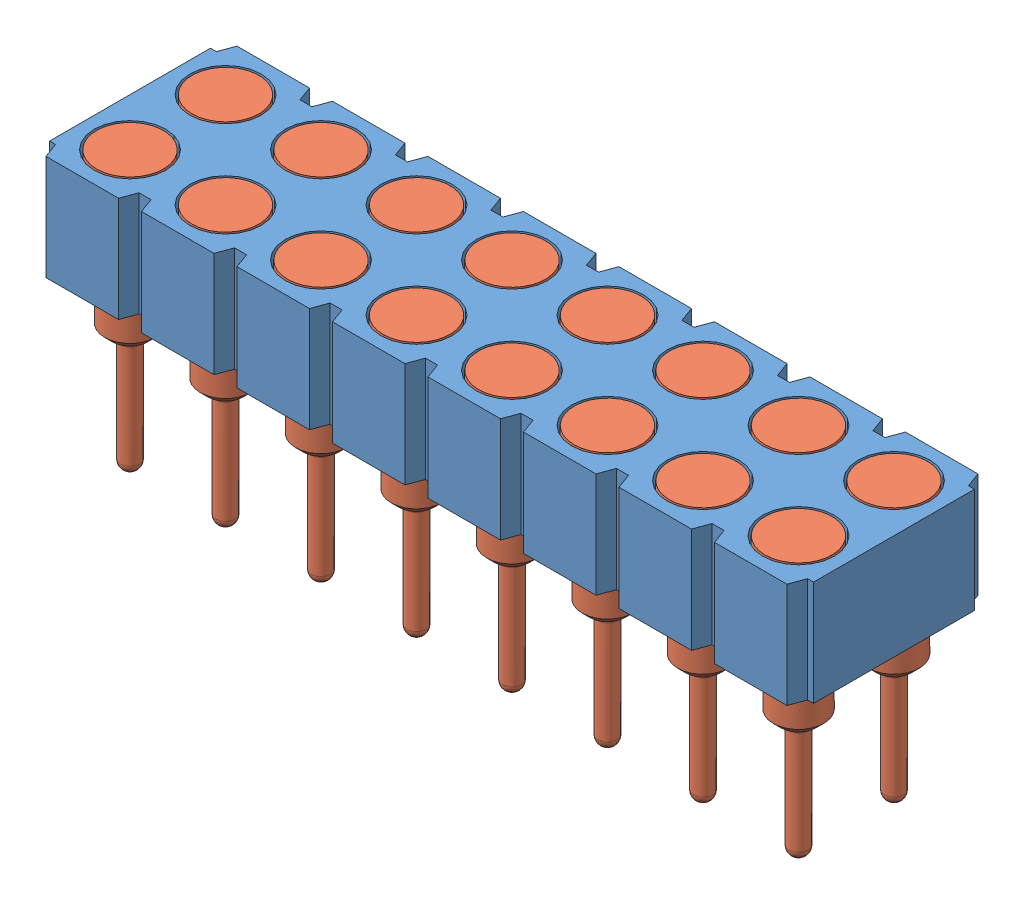
SolidWorks assembly mill-max-419-10-216-00-001000, configuration MillMaxsldprt2014419-XX-XXX-00-0010001610uGoldoverNickelPage14off. Lengths in mm.
Overall size (20.32 7.37 5.08).
17 component instances, 2 part files, 4 mates.
Components (placement in the parent):
- mill-max-419-10-216-00-001000_P4XX-21-010-00-000000-1: mill-max-419-10-216-00-001000_P4XX-21-010-00-000000 [P416-21-010-00-000000] at origin size (20.32 2.79 5.08)
- mill-max-419-10-216-00-001000_1942-1: mill-max-419-10-216-00-001000_1942 [Default] at (0.9644 0 -1.27) x (0 -1 0) z (0 0 1) size (7.37 1.78 1.78)
- mill-max-419-10-216-00-001000_1942-35: mill-max-419-10-216-00-001000_1942 [Default] at (0.9644 0 -3.81) x (0 -1 0) z (0 0 1) size (7.37 1.78 1.78)
- mill-max-419-10-216-00-001000_1942-36: mill-max-419-10-216-00-001000_1942 [Default] at (3.5044 0 -3.81) x (0 -1 0) z (0 0 1) size (7.37 1.78 1.78)
- mill-max-419-10-216-00-001000_1942-20: mill-max-419-10-216-00-001000_1942 [Default] at (3.5044 0 -1.27) x (0 -1 0) z (0 0 1) size (7.37 1.78 1.78)
- mill-max-419-10-216-00-001000_1942-37: mill-max-419-10-216-00-001000_1942 [Default] at (6.0444 0 -3.81) x (0 -1 0) z (0 0 1) size (7.37 1.78 1.78)
- mill-max-419-10-216-00-001000_1942-38: mill-max-419-10-216-00-001000_1942 [Default] at (8.5844 0 -3.81) x (0 -1 0) z (0 0 1) size (7.37 1.78 1.78)
- mill-max-419-10-216-00-001000_1942-39: mill-max-419-10-216-00-001000_1942 [Default] at (11.1244 0 -3.81) x (0 -1 0) z (0 0 1) size (7.37 1.78 1.78)
- mill-max-419-10-216-00-001000_1942-40: mill-max-419-10-216-00-001000_1942 [Default] at (13.6644 0 -3.81) x (0 -1 0) z (0 0 1) size (7.37 1.78 1.78)
- mill-max-419-10-216-00-001000_1942-41: mill-max-419-10-216-00-001000_1942 [Default] at (16.2044 0 -3.81) x (0 -1 0) z (0 0 1) size (7.37 1.78 1.78)
- mill-max-419-10-216-00-001000_1942-42: mill-max-419-10-216-00-001000_1942 [Default] at (18.7444 0 -3.81) x (0 -1 0) z (0 0 1) size (7.37 1.78 1.78)
- mill-max-419-10-216-00-001000_1942-29: mill-max-419-10-216-00-001000_1942 [Default] at (6.0444 0 -1.27) x (0 -1 0) z (0 0 1) size (7.37 1.78 1.78)
- mill-max-419-10-216-00-001000_1942-30: mill-max-419-10-216-00-001000_1942 [Default] at (8.5844 0 -1.27) x (0 -1 0) z (0 0 1) size (7.37 1.78 1.78)
- mill-max-419-10-216-00-001000_1942-31: mill-max-419-10-216-00-001000_1942 [Default] at (11.1244 0 -1.27) x (0 -1 0) z (0 0 1) size (7.37 1.78 1.78)
- mill-max-419-10-216-00-001000_1942-32: mill-max-419-10-216-00-001000_1942 [Default] at (13.6644 0 -1.27) x (0 -1 0) z (0 0 1) size (7.37 1.78 1.78)
- mill-max-419-10-216-00-001000_1942-33: mill-max-419-10-216-00-001000_1942 [Default] at (16.2044 0 -1.27) x (0 -1 0) z (0 0 1) size (7.37 1.78 1.78)
- mill-max-419-10-216-00-001000_1942-34: mill-max-419-10-216-00-001000_1942 [Default] at (18.7444 0 -1.27) x (0 -1 0) z (0 0 1) size (7.37 1.78 1.78)
Mates (geometry in assembly coordinates):
- Concentric1: concentric aligned: circle of mill-max-419-10-216-00-001000_1942-1; circle of mill-max-419-10-216-00-001000_P4XX-21-010-00-000000-1
- Coincident1: coincident aligned: plane of mill-max-419-10-216-00-001000_P4XX-21-010-00-000000-1 through (-0.1456 0 -4.68) normal (0 1 0); plane of mill-max-419-10-216-00-001000_1942-1 through (0.9644 0 -1.27) normal (0 1 0)
- Concentric2: concentric: circle of mill-max-419-10-216-00-001000_1942-35; circle of mill-max-419-10-216-00-001000_P4XX-21-010-00-000000-1
- Coincident2: coincident aligned: plane of mill-max-419-10-216-00-001000_P4XX-21-010-00-000000-1 through (-0.1456 0 -4.68) normal (0 1 0); plane of mill-max-419-10-216-00-001000_1942-35 through (0.9644 0 -3.81) normal (0 1 0)
